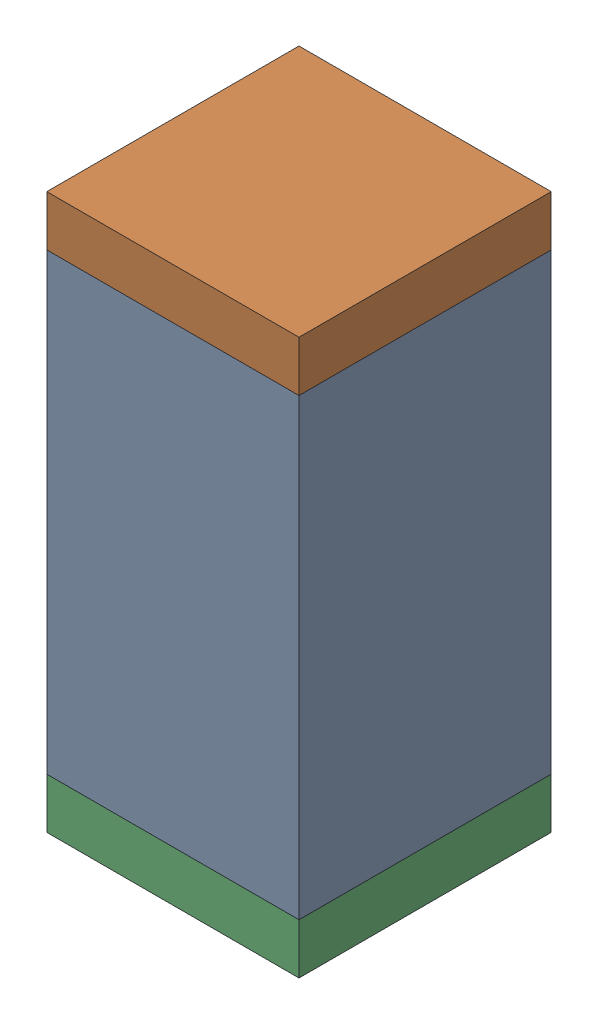
SolidWorks assembly C20, configuration Default. Lengths in mm.
Overall size (0.5 1.1 0.5).
6 component instances, 2 part files, 0 mates.
Components (placement in the parent):
- 791586336-1: 791586336 [Default] at (113.05 17.15 0) size (0.5 0.9 0.5)
  - Extruded_8-1: Extruded_8 [Default] at origin size (0.5 0.9 0.5)
- 810157360-1: 810157360 [Default] at (113.05 17.65 0) size (0.5 0.1 0.5)
  - Extruded_9-1: Extruded_9 [Default] at origin size (0.5 0.1 0.5)
- 810157360-2: 810157360 [Default] at (113.05 16.65 0) size (0.5 0.1 0.5)
  - Extruded_9-1: Extruded_9 [Default] at origin size (0.5 0.1 0.5)
